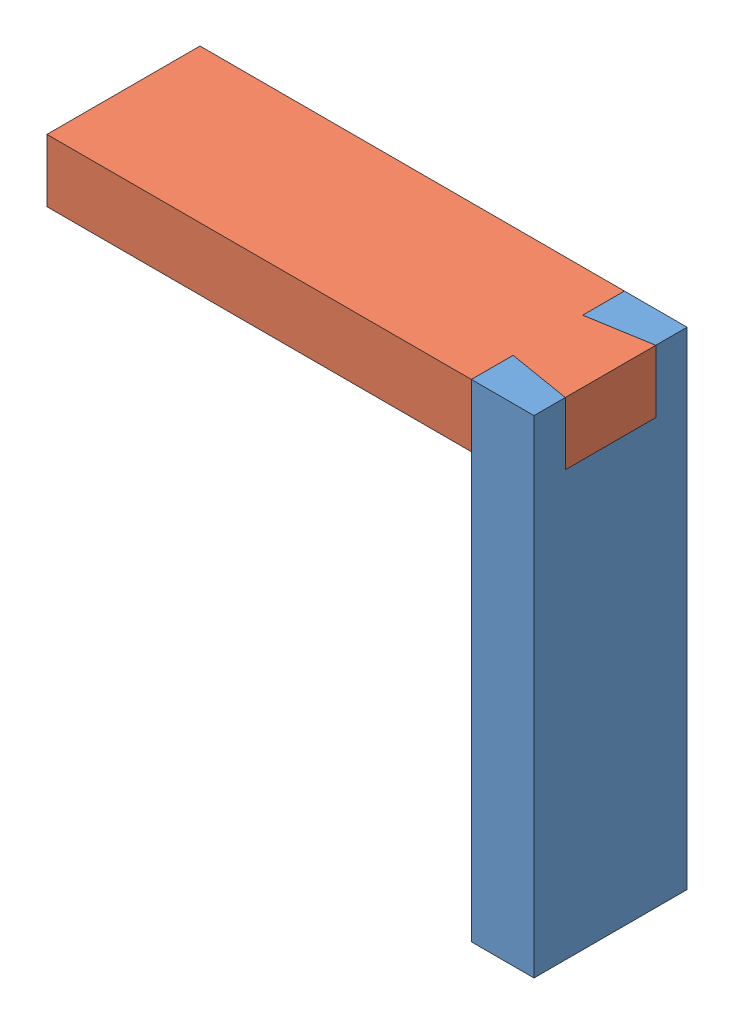
SolidWorks assembly BOX DOVETAIL, configuration Default. Lengths in mm.
Overall size (140 140 44).
2 component instances, 2 part files, 3 mates.
Components (placement in the parent):
- PINS-1: PINS [Default] at (-141.654 -52.7326 89.9316) size (18 140 44)
- TAILS-1: TAILS [Default] at (-123.654 69.2674 89.9316) size (140 18 44)
Mates (geometry in assembly coordinates):
- Coincident1: coincident aligned: plane of PINS-1 through (-123.654 87.2674 89.9316) normal (0 1 0); plane of TAILS-1 through (-123.654 87.2674 45.9316) normal (0 1 0)
- Coincident2: coincident anti-aligned: plane of PINS-1 through (-141.654 87.2674 89.9316) normal (-1 0 0); plane of TAILS-1 through (-141.654 69.2664 77.9316) normal (1 0 0)
- Coincident4: coincident aligned: line of PINS-1 through (-123.654 69.2674 80.9316) axis (0 1 0); line of TAILS-1 through (-123.654 69.2674 80.9316) axis (0 1 0)
